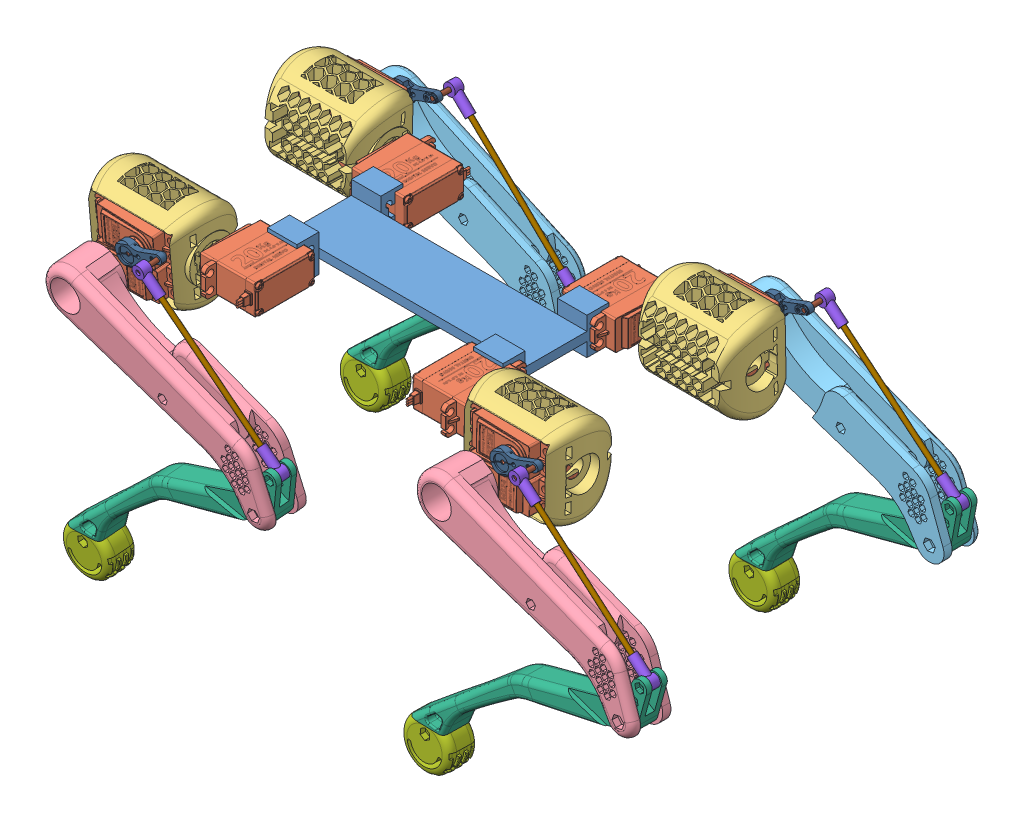
SolidWorks assembly Main_URDF_Assembly, configuration Default. Lengths in mm.
Overall size (432.52 227.74 243.72).
49 component instances, 11 part files, 112 mates.
Components (placement in the parent):
- Main_Body-1: Main_Body [Default] at (5.0922 136.3443 221.2659) size (160 25 72)
- DS3218MG_MS24_Digital_Servo_270-1: DS3218MG_MS24_Digital_Servo_270 [Default] at (145.0922 136.3151 160.5847) x (0 -1 0) z (0 0 1) size (20.1 45.99 55.6)
- DS3218MG_MS24_Digital_Servo_270-2: DS3218MG_MS24_Digital_Servo_270 [Default] at (145.0922 136.3151 281.9471) x (0 1 0) z (0 0 -1) size (20.1 45.99 55.6)
- DS3218MG_MS24_Digital_Servo_270-3: DS3218MG_MS24_Digital_Servo_270 [Default] at (-14.9078 136.3151 160.5847) x (0 1 0) z (0 0 1) size (20.1 45.99 55.6)
- DS3218MG_MS24_Digital_Servo_270-4: DS3218MG_MS24_Digital_Servo_270 [Default] at (-14.9078 136.3151 281.9471) x (0 -1 0) z (0 0 -1) size (20.1 45.99 55.6)
- HipJoint-1: HipJoint [Default] at (191.8422 136.3151 281.9471) x (1 0 0) z (0 0.020151 0.999797) size (67.23 58.77 49.18)
- HipJoint-2: HipJoint [Default] at (191.8422 136.3151 160.5847) x (1 0 0) z (0 0.018154 -0.999835) size (67.23 58.77 49.18)
- HipJoint-3: HipJoint [Default] at (-61.6578 136.3151 160.5847) x (-1 0 0) z (0 -0.032164 -0.999483) size (67.23 58.77 49.18)
- HipJoint-4: HipJoint [Default] at (-61.6578 136.3151 281.9471) x (-1 0 0) z (0 -0.089213 0.996013) size (67.23 58.77 49.18)
- DS3218MG_MS24_Digital_Servo_270-5: DS3218MG_MS24_Digital_Servo_270 [Default] at (-51.4078 146.0222 296.8726) x (0 -0.996013 -0.089213) z (-1 0 0) size (20.1 45.99 55.6)
- DS3218MG_MS24_Digital_Servo_270-6: DS3218MG_MS24_Digital_Servo_270 [Default] at (-71.9078 124.11 294.91) x (0 0.996013 0.089213) z (1 0 0) size (20.1 45.99 55.6)
- DS3218MG_MS24_Digital_Servo_270-7: DS3218MG_MS24_Digital_Servo_270 [Default] at (181.5922 125.5994 296.1659) x (0 0.999797 -0.020151) z (1 0 0) size (20.1 45.99 55.6)
- DS3218MG_MS24_Digital_Servo_270-8: DS3218MG_MS24_Digital_Servo_270 [Default] at (202.0922 147.6949 295.7206) x (0 -0.999797 0.020151) z (-1 0 0) size (20.1 45.99 55.6)
- DS3218MG_MS24_Digital_Servo_270-10: DS3218MG_MS24_Digital_Servo_270 [Default] at (201.5922 147.5674 146.7867) x (0 0.999835 0.018154) z (-1 0 0) size (20.1 45.99 55.6)
- DS3218MG_MS24_Digital_Servo_270-11: DS3218MG_MS24_Digital_Servo_270 [Default] at (182.0922 125.5711 146.3873) x (0 -0.999835 -0.018154) z (1 0 0) size (20.1 45.99 55.6)
- DS3218MG_MS24_Digital_Servo_270-12: DS3218MG_MS24_Digital_Servo_270 [Default] at (-71.4078 124.7705 146.949) x (0 -0.999483 0.032164) z (1 0 0) size (20.1 45.99 55.6)
- DS3218MG_MS24_Digital_Servo_270-13: DS3218MG_MS24_Digital_Servo_270 [Default] at (-51.9078 146.8591 146.2382) x (0 0.999483 -0.032164) z (-1 0 0) size (20.1 45.99 55.6)
- Left_Thigh-1: Left_Thigh [Default] at (238.4344 106.9954 326.3469) x (0 0.020151 0.999797) z (-0.94737 0.320075 -0.006451) size (26.29 49.21 165.28)
- Left_Thigh-2: Left_Thigh [Default] at (-16.0368 99.6656 322.6398) x (0 -0.089213 0.996013) z (-0.931184 0.363097 0.032523) size (26.29 49.21 165.28)
- Right_Thigh-1: Right_Thigh [Default] at (238.6676 105.2996 162.2219) x (0 -0.018154 0.999835) z (-0.942923 0.332955 0.006045) size (26.29 49.21 165.28)
- Right_Thigh-2: Right_Thigh [Default] at (-15.4072 103.7636 163.8334) x (0 0.032164 0.999483) z (-0.933343 0.358799 -0.011546) size (26.29 49.21 165.28)
- Leg_Universal-1: Leg_Universal [Default] at (-18.5337 13.2297 315.3997) x (0 -0.089213 0.996013) z (-0.987227 -0.158687 -0.014214) size (27.56 93.87 164.52)
- Leg_Universal-2: Leg_Universal [Default] at (-18.251 17.1977 120.0951) x (0 0.032164 0.999483) z (-0.989939 -0.14142 0.004551) size (27.56 93.87 164.52)
- Leg_Universal-3: Leg_Universal [Default] at (237.16 22.9219 114.2185) x (0 -0.018154 0.999835) z (-0.990021 -0.1409 -0.002558) size (27.56 93.87 164.52)
- Leg_Universal-4: Leg_Universal [Default] at (235.6218 28.8095 328.4229) x (0 0.020151 0.999797) z (-0.996606 -0.082305 0.001659) size (27.56 93.87 164.52)
- Feet-1: Feet [Default] at (-76.7895 -34.0885 310.9104) x (0 -0.089213 0.996013) z (-0.998583 -0.052998 -0.004747) size (22.41 28.94 33.98)
- Feet-2: Feet [Default] at (173.8572 -14.0583 329.0368) x (0 -0.020151 -0.999797) z (0.999703 -0.024346 0.000491) size (22.41 28.94 33.98)
- Feet-3: Feet [Default] at (178.5295 -23.4953 113.6258) x (0 -0.018154 0.999835) z (-0.999401 -0.034613 -0.000628) size (22.41 28.94 33.98)
- Feet-4: Feet [Default] at (-76.8547 -29.2243 121.8391) x (0 0.032164 0.999483) z (-0.99938 -0.035176 0.001132) size (22.41 28.94 33.98)
- Ball_Bearing_End_Joint-1: Ball_Bearing_End_Joint [Default] at (314.8505 81.1585 327.1177) x (0.639096 0.768971 -0.015498) z (0 -0.020151 -0.999797) size (8 20 6)
- Ball_Bearing_End_Joint-2: Ball_Bearing_End_Joint [Default] at (313.1644 79.8517 115.5023) x (0.650252 0.759593 0.013792) z (0 0.018154 -0.999835) size (8 20 6)
- Ball_Bearing_End_Joint-3: Ball_Bearing_End_Joint [Default] at (56.3978 71.3675 320.3561) x (0.685285 0.725371 0.064972) z (0 0.089213 -0.996013) size (8 20 6)
- Ball_Bearing_End_Joint-4: Ball_Bearing_End_Joint [Default] at (57.7206 74.1637 118.512) x (0.67212 0.74006 -0.023816) z (0 -0.032164 -0.999483) size (8 20 6)
- Long_Metal_Rod-1: Long_Metal_Rod [Default] at (13.4296 111.6381 323.9631) x (-0.174888 -0.098859 -0.979613) z (-0.728275 0.682553 0.061136) size (3 3 100)
- Long_Metal_Rod-2: Long_Metal_Rod [Default] at (14.0344 113.7983 117.2365) x (0.411304 0.478318 0.775913) z (-0.740443 0.671772 -0.021618) size (3 3 100)
- Long_Metal_Rod-3: Long_Metal_Rod [Default] at (269.472 118.8575 326.3579) x (0.046921 0.076552 0.995961) z (0.769127 -0.638967 0.012878) size (3 3 100)
- Long_Metal_Rod-4: Long_Metal_Rod [Default] at (268.341 118.2103 116.1987) x (-0.048668 -0.074954 0.995999) z (-0.759718 0.650145 0.011805) size (3 3 100)
- Servo_arm_25T-1: Servo_arm_25T [Default] at (-51.9078 146.219 126.3485) x (-0.94707 -0.320861 0.010325) z (-0.321027 0.94658 -0.030461) size (33.87 4.68 15)
- Servo_arm_25T-2: Servo_arm_25T [Default] at (201.5922 147.9287 126.89) x (-0.932997 -0.359824 -0.006533) z (-0.359884 0.932843 0.016938) size (33.87 4.68 15)
- Servo_arm_25T-3: Servo_arm_25T [Default] at (202.0922 148.0959 315.6166) x (-0.936228 -0.351321 0.007081) z (0.351392 -0.936038 0.018866) size (33.87 4.68 15)
- Servo_arm_25T-4: Servo_arm_25T [Default] at (-51.4078 144.2469 316.6933) x (-0.930604 -0.364568 -0.032654) z (0.366028 -0.926893 -0.083022) size (33.87 4.68 15)
- Ball_Bearing_End_Joint-5: Ball_Bearing_End_Joint [Default] at (-29.5386 151.9087 327.5702) x (0.685285 0.725371 0.064972) z (0 -0.089213 0.996013) size (8 20 6)
- Ball_Bearing_End_Joint-6: Ball_Bearing_End_Joint [Default] at (224.0935 156.5565 325.5981) x (-0.639096 -0.768971 0.015498) z (0 -0.020151 -0.999797) size (8 20 6)
- Ball_Bearing_End_Joint-7: Ball_Bearing_End_Joint [Default] at (223.5176 156.5688 116.8952) x (0.650252 0.759593 0.013792) z (0 -0.018154 0.999835) size (8 20 6)
- Ball_Bearing_End_Joint-8: Ball_Bearing_End_Joint [Default] at (-29.6517 153.4328 115.9611) x (-0.67212 -0.74006 0.023816) z (0 -0.032164 -0.999483) size (8 20 6)
- Short_Metal_Rod-1: Short_Metal_Rod [Default] at (-29.5386 152.3102 323.0881) x (0.999839 0.017882 0.001602) z (0 -0.089213 0.996013) size (3 3 16.55)
- Short_Metal_Rod-2: Short_Metal_Rod [Default] at (224.0935 156.4658 321.099) x (1 0 0) z (0 0.020151 0.999797) size (3 3 16.55)
- Short_Metal_Rod-3: Short_Metal_Rod [Default] at (223.5176 156.4191 125.1439) x (1 0.000002 0) z (0 -0.018154 0.999835) size (3 3 16.55)
- Short_Metal_Rod-4: Short_Metal_Rod [Default] at (-29.6517 153.6981 124.2068) x (0.999998 -0.001781 0.000057) z (0 0.032164 0.999483) size (3 3 16.55)
Mates (geometry in assembly coordinates):
- Coincident1: coincident anti-aligned: plane of Body-1 through (145.0922 136.3443 251.9471) normal (0 0 1); plane of DS3218MG MS24 Digital Servo 270-2 through (125.0922 126.3151 251.9471) normal (0 0 -1)
- Coincident2: coincident anti-aligned: plane of Body-1 through (145.0922 126.3151 221.2659) normal (0 1 0); plane of DS3218MG MS24 Digital Servo 270-2 through (156.0922 126.3151 290.9471) normal (0 -1 0)
- Coincident3: coincident anti-aligned: plane of Body-1 through (145.0922 136.3443 221.2659) normal (1 0 0); plane of DS3218MG MS24 Digital Servo 270-2 through (145.0922 145.3151 254.9471) normal (-1 0 0)
- Coincident4: coincident anti-aligned: plane of Body-1 through (145.0922 126.3151 221.2659) normal (0 1 0); plane of DS3218MG MS24 Digital Servo 270-1 through (156.0922 126.3151 189.5847) normal (0 -1 0)
- Coincident5: coincident anti-aligned: plane of Body-1 through (145.0922 136.3443 221.2659) normal (1 0 0); plane of DS3218MG MS24 Digital Servo 270-1 through (145.0922 127.3151 187.5847) normal (-1 0 0)
- Coincident6: coincident anti-aligned: plane of Body-1 through (145.0922 136.3443 190.5847) normal (0 0 -1); plane of DS3218MG MS24 Digital Servo 270-1 through (125.0922 146.3151 190.5847) normal (0 0 1)
- Coincident7: coincident anti-aligned: plane of Body-1 through (-14.9078 126.3151 221.2659) normal (0 1 0); plane of DS3218MG MS24 Digital Servo 270-3 through (-25.9078 126.3151 151.5847) normal (0 -1 0)
- Coincident8: coincident anti-aligned: plane of Body-1 through (-14.9078 136.3443 190.5847) normal (0 0 -1); plane of DS3218MG MS24 Digital Servo 270-3 through (5.0922 126.3151 190.5847) normal (0 0 1)
- Coincident9: coincident anti-aligned: plane of Body-1 through (-14.9078 136.3443 221.2659) normal (-1 0 0); plane of DS3218MG MS24 Digital Servo 270-3 through (-14.9078 145.3151 187.5847) normal (1 0 0)
- Coincident15: coincident anti-aligned: plane of Body-1 through (-14.9078 136.3443 251.9471) normal (0 0 1); plane of DS3218MG MS24 Digital Servo 270-4 through (5.0922 146.3151 251.9471) normal (0 0 -1)
- Coincident16: coincident anti-aligned: plane of Body-1 through (-14.9078 126.3151 221.2659) normal (0 1 0); plane of DS3218MG MS24 Digital Servo 270-4 through (5.0922 126.3151 291.9471) normal (0 -1 0)
- Coincident17: coincident anti-aligned: plane of Body-1 through (-14.9078 136.3443 221.2659) normal (-1 0 0); plane of DS3218MG MS24 Digital Servo 270-4 through (-14.9078 127.3151 254.9471) normal (1 0 0)
- Concentric1: concentric aligned: circle of DS3218MG MS24 Digital Servo 270-2; circle of HipJoint-1
- Distance2: distance = 0 mm anti-aligned: plane of DS3218MG MS24 Digital Servo 270-2 through (163.4922 136.3151 281.9471) normal (1 0 0); plane of HipJoint-1 through (163.4922 136.3151 281.9471) normal (-1 0 0)
- Concentric2: concentric aligned: circle of DS3218MG MS24 Digital Servo 270-1; circle of HipJoint-2
- Distance1: distance = 0 mm anti-aligned: plane of HipJoint-2 through (163.4922 136.3151 160.5847) normal (-1 0 0); plane of DS3218MG MS24 Digital Servo 270-1 through (163.4922 136.3151 160.5847) normal (1 0 0)
- Concentric3: concentric aligned: circle of DS3218MG MS24 Digital Servo 270-3; circle of HipJoint-3
- Distance3: distance = 0 mm anti-aligned: plane of HipJoint-3 through (-33.3078 136.3151 160.5847) normal (1 0 0); plane of DS3218MG MS24 Digital Servo 270-3 through (-33.3078 136.3151 160.5847) normal (-1 0 0)
- Concentric4: concentric aligned: circle of DS3218MG MS24 Digital Servo 270-4; circle of HipJoint-4
- Distance4: distance = 0 mm anti-aligned: plane of HipJoint-4 through (-33.3078 136.3151 281.9471) normal (1 0 0); plane of DS3218MG MS24 Digital Servo 270-4 through (-33.3078 136.3151 281.9471) normal (-1 0 0)
- Coincident23: coincident anti-aligned: plane of HipJoint-4 through (-81.9078 137.5641 268.0029) normal (1 0 0); plane of DS3218MG_MS24_Digital_Servo_270-6 through (-81.9078 115.9341 274.0976) normal (-1 0 0)
- Coincident24: coincident anti-aligned: plane of HipJoint-4 through (-61.6578 135.0661 295.8913) normal (0 -0.089213 0.996013); plane of DS3218MG_MS24_Digital_Servo_270-6 through (-44.9078 133.0741 295.7129) normal (0 0.089213 -0.996013)
- Coincident25: coincident anti-aligned: plane of HipJoint-4 through (-61.6578 136.5681 267.9137) normal (0 -0.996013 -0.089213); plane of DS3218MG_MS24_Digital_Servo_270-6 through (-81.9078 135.8543 275.8818) normal (0 0.996013 0.089213)
- Coincident26: coincident anti-aligned: plane of HipJoint-4 through (-41.4078 137.5641 268.0029) normal (-1 0 0); plane of DS3218MG_MS24_Digital_Servo_270-5 through (-41.4078 157.7666 277.8445) normal (1 0 0)
- Coincident27: coincident anti-aligned: plane of HipJoint-4 through (-61.6578 135.0661 295.8913) normal (0 -0.089213 0.996013); plane of DS3218MG_MS24_Digital_Servo_270-5 through (-78.4078 137.0581 296.0697) normal (0 0.089213 -0.996013)
- Coincident28: coincident anti-aligned: plane of HipJoint-4 through (-61.6578 138.5601 268.0922) normal (0 0.996013 0.089213); plane of DS3218MG_MS24_Digital_Servo_270-5 through (-41.4078 137.8464 276.0603) normal (0 -0.996013 -0.089213)
- Coincident29: coincident anti-aligned: plane of HipJoint-1 through (212.0922 136.033 267.95) normal (-1 0 0); plane of DS3218MG MS24 Digital Servo 270-8 through (212.0922 157.2899 275.5232) normal (1 0 0)
- Coincident30: coincident anti-aligned: plane of HipJoint-1; plane of DS3218MG MS24 Digital Servo 270-8
- Coincident31: coincident anti-aligned: plane of HipJoint-1; plane of DS3218MG MS24 Digital Servo 270-8
- Coincident32: coincident anti-aligned: plane of HipJoint-1 through (171.5922 136.033 267.95) normal (1 0 0); plane of DS3218MG MS24 Digital Servo 270-7 through (171.5922 115.1984 276.3715) normal (-1 0 0)
- Coincident33: coincident anti-aligned: plane of HipJoint-1; plane of DS3218MG MS24 Digital Servo 270-7
- Coincident34: coincident anti-aligned: plane of HipJoint-1; plane of DS3218MG MS24 Digital Servo 270-7
- Concentric6: concentric aligned: circle of DS3218MG MS24 Digital Servo 270-6; circle of Left Thigh-2
- Distance18: distance = 2 mm anti-aligned: plane of Left_Thigh-2 through (-71.9078 122.29 315.2286) normal (0 0.089213 -0.996013); plane of DS3218MG_MS24_Digital_Servo_270-6 through (-71.9078 122.4684 313.2366) normal (0 -0.089213 0.996013)
- Concentric7: concentric aligned: circle of DS3218MG MS24 Digital Servo 270-7; circle of Left Thigh-1
- Distance19: distance = 2 mm anti-aligned: plane of Left_Thigh-1 through (181.5922 126.0105 316.5618) normal (0 -0.020151 -0.999797); plane of DS3218MG_MS24_Digital_Servo_270-7 through (181.5922 125.9702 314.5622) normal (0 0.020151 0.999797)
- Coincident37: coincident anti-aligned: plane of HipJoint-2 through (212.0922 136.0609 174.5824) normal (-1 0 0); plane of DS3218MG_MS24_Digital_Servo_270-11 through (212.0922 135.2063 166.5656) normal (1 0 0)
- Coincident38: coincident anti-aligned: plane of HipJoint-2 through (191.8422 135.0611 174.5643) normal (0 -0.999835 -0.018154); plane of DS3218MG_MS24_Digital_Servo_270-11 through (172.0922 135.2063 166.5656) normal (0 0.999835 0.018154)
- Coincident39: coincident anti-aligned: plane of HipJoint-2 through (191.8422 136.5692 146.587) normal (0 0.018154 -0.999835); plane of DS3218MG_MS24_Digital_Servo_270-11 through (209.0922 116.5725 146.224) normal (0 -0.018154 0.999835)
- Coincident40: coincident anti-aligned: plane of HipJoint-2 through (171.5922 136.0609 174.5824) normal (1 0 0); plane of DS3218MG_MS24_Digital_Servo_270-10 through (171.5922 137.206 166.6019) normal (-1 0 0)
- Coincident41: coincident anti-aligned: plane of HipJoint-2 through (191.8422 137.0608 174.6006) normal (0 0.999835 0.018154); plane of DS3218MG_MS24_Digital_Servo_270-10 through (211.5922 137.206 166.6019) normal (0 -0.999835 -0.018154)
- Coincident42: coincident anti-aligned: plane of HipJoint-2 through (191.8422 136.5692 146.587) normal (0 0.018154 -0.999835); plane of DS3218MG_MS24_Digital_Servo_270-10 through (174.5922 156.5659 146.9501) normal (0 -0.018154 0.999835)
- Coincident43: coincident anti-aligned: plane of HipJoint-3 through (-41.4078 136.7654 174.5775) normal (-1 0 0); plane of DS3218MG MS24 Digital Servo 270-11 through (-41.4078 135.4086 166.617) normal (1 0 0)
- Coincident44: coincident anti-aligned: plane of HipJoint-3 through (-61.6578 135.8648 146.592) normal (0 -0.032164 -0.999483); plane of DS3218MG MS24 Digital Servo 270-11 through (-44.4078 115.7752 147.2385) normal (0 0.032164 0.999483)
- Coincident45: coincident anti-aligned: plane of HipJoint-3 through (-61.6578 115.6763 175.2561) normal (0 0.999483 -0.032164); plane of DS3218MG MS24 Digital Servo 270-11 through (-81.4078 115.419 167.2603) normal (0 -0.999483 0.032164)
- Coincident46: coincident anti-aligned: plane of HipJoint-3 through (-81.9078 136.7654 174.5775) normal (1 0 0); plane of DS3218MG MS24 Digital Servo 270-12 through (-81.9078 137.5075 166.5495) normal (-1 0 0)
- Coincident47: coincident anti-aligned: plane of HipJoint-3 through (-61.6578 137.7649 174.5453) normal (0 0.999483 -0.032164); plane of DS3218MG MS24 Digital Servo 270-12 through (-41.9078 137.5075 166.5495) normal (0 -0.999483 0.032164)
- Coincident48: coincident anti-aligned: plane of HipJoint-3 through (-61.6578 135.8648 146.592) normal (0 -0.032164 -0.999483); plane of DS3218MG MS24 Digital Servo 270-12 through (-78.9078 155.8544 145.9487) normal (0 0.032164 0.999483)
- Concentric8: concentric aligned: circle of DS3218MG MS24 Digital Servo 270-9; circle of Right Thigh-1
- Distance20: distance = 2 mm anti-aligned: plane of DS3218MG_MS24_Digital_Servo_270-11 through (182.0922 125.9051 127.9904) normal (0 0.018154 -0.999835); plane of Right_Thigh-1 through (182.0922 125.9414 125.9907) normal (0 -0.018154 0.999835)
- Concentric9: concentric anti-aligned: circle of DS3218MG MS24 Digital Servo 270-11; circle of Right Thigh-2
- Distance21: distance = 2 mm anti-aligned: plane of DS3218MG MS24 Digital Servo 270-11 through (-71.4078 124.1787 128.5585) normal (0 -0.032164 -0.999483); plane of Right Thigh-2 through (-71.4078 124.1144 126.5596) normal (0 0.032164 0.999483)
- Concentric10: concentric anti-aligned: circle of Left Thigh-2; circle of Leg_Universal-1
- Distance10: distance = 0 mm anti-aligned: plane of Leg_Universal-1 through (-18.5337 12.6052 322.3718) normal (0 -0.089213 0.996013); plane of Left_Thigh-2 through (-16.0368 98.9965 330.1099) normal (0 0.089213 -0.996013)
- Concentric11: concentric anti-aligned: circle of Left Thigh-1; circle of Leg_Universal-4
- Distance11: distance = 0 mm anti-aligned: plane of Left_Thigh-1 through (238.4344 107.1466 333.8454) normal (0 -0.020151 -0.999797); plane of Leg_Universal-4 through (235.6218 28.9505 335.4214) normal (0 0.020151 0.999797)
- Concentric12: concentric anti-aligned: circle of Right Thigh-1; circle of Leg_Universal-3
- Distance12: distance = 0 mm anti-aligned: plane of Leg_Universal-3 through (237.16 23.049 107.2197) normal (0 0.018154 -0.999835); plane of Right_Thigh-1 through (238.6676 106.2709 108.7308) normal (0 -0.018154 0.999835)
- Concentric13: concentric anti-aligned: circle of Right Thigh-2; circle of Leg_Universal-2
- Distance13: distance = 0 mm anti-aligned: plane of Leg_Universal-2 through (-18.251 16.9726 113.0987) normal (0 -0.032164 -0.999483); plane of Right Thigh-2 through (-15.4072 102.0429 110.3611) normal (0 0.032164 0.999483)
- Coincident55: coincident anti-aligned: plane of Leg_Universal-1 through (-72.9089 10.7006 311.1571) normal (0.998583 0.052998 0.004747); plane of Feet-1 through (-70.2275 -39.7541 310.4029) normal (-0.998583 -0.052998 -0.004747)
- Coincident56: coincident anti-aligned: plane of Leg_Universal-1 through (-18.5337 12.8728 319.3837) normal (0 -0.089213 0.996013); plane of Feet-1 through (-76.4686 -40.4645 314.6063) normal (0 0.089213 -0.996013)
- Coincident57: coincident anti-aligned: plane of Leg_Universal-1 through (-16.4376 -25.0578 301.9302) normal (0.053211 -0.994602 -0.089087); plane of Feet-1 through (-77.054 -28.0915 299.5944) normal (-0.053211 0.994602 0.089087)
- Coincident58: coincident anti-aligned: plane of Leg_Universal-4 through (235.6218 28.8901 332.4221) normal (0 0.020151 0.999797); plane of Feet-2 through (173.7104 -19.9991 333.4074) normal (0 -0.020151 -0.999797)
- Coincident59: coincident anti-aligned: plane of Leg_Universal-4 through (181.1856 30.0546 324.397) normal (0.999703 -0.024346 0.000491); plane of Feet-2 through (179.9585 -20.2369 329.1613) normal (-0.999703 0.024346 -0.000491)
- Coincident60: coincident anti-aligned: plane of Leg_Universal-4 through (234.6625 -10.7646 319.2184) normal (-0.024351 -0.9995 0.020145); plane of Feet-2 through (173.9782 -8.8524 340.7401) normal (0.024351 0.9995 -0.020145)
- Coincident61: coincident anti-aligned: plane of Leg_Universal-3 through (237.16 22.9945 110.2192) normal (0 0.018154 -0.999835); plane of Feet-3 through (178.7383 -29.443 109.2671) normal (0 -0.018154 0.999835)
- Coincident62: coincident anti-aligned: plane of Leg_Universal-3 through (170.7475 20.6944 110.1774) normal (-0.999401 -0.034613 -0.000628); plane of Feet-3 through (172.492 -29.7364 113.5125) normal (0.999401 0.034613 0.000628)
- Coincident63: coincident anti-aligned: plane of Leg_Universal-3 through (238.5237 -16.2587 103.5055) normal (0.034619 -0.999236 -0.018143); plane of Feet-3 through (178.3575 -18.3142 101.9121) normal (-0.034619 0.999236 0.018143)
- Coincident64: coincident anti-aligned: plane of Feet-4 through (-82.8886 -35.4667 122.04) normal (0.99938 0.035176 -0.001132); plane of Leg_Universal-2 through (-84.6622 14.7315 116.1724) normal (-0.99938 -0.035176 0.001132)
- Coincident66: coincident anti-aligned: plane of Leg_Universal-2 through (-16.8646 -22.4714 111.3665) normal (0.035194 -0.998863 0.032144); plane of Feet-4 through (-77.0297 -24.6391 109.8796) normal (-0.035194 0.998863 -0.032144)
- Coincident67: coincident anti-aligned: plane of Leg_Universal-2 through (-18.251 17.0691 116.0971) normal (0 -0.032164 -0.999483); plane of Feet-4 through (-76.6425 -35.3836 117.7851) normal (0 0.032164 0.999483)
- Coincident68: coincident aligned: circle of Leg_Universal-4; circle of ball bearing end joint-1
- Coincident69: coincident anti-aligned: circle of Leg_Universal-3; circle of ball bearing end joint-2
- Coincident70: coincident anti-aligned: circle of Leg_Universal-2; circle of ball bearing end joint-4
- Coincident71: coincident aligned: circle of Leg_Universal-1; circle of ball bearing end joint-3
- Concentric14: concentric aligned: cylinder of Ball_Bearing_End_Joint-2 through (306.3269 85.703 115.6085) axis (-0.759718 0.650145 0.011805) radius 1.5; cylinder of Long_Metal_Rod-4 through (306.3269 85.703 115.6085) axis (-0.759718 0.650145 0.011805) radius 1.5
- Concentric15: concentric anti-aligned: cylinder of ball bearing end joint-1 through (307.9284 86.9092 327.0018) axis (-0.769127 0.638967 -0.012878) radius 1.5; cylinder of long-3 through (231.0157 150.8058 325.714) axis (0.769127 -0.638967 0.012878) radius 1.5
- Concentric16: concentric aligned: cylinder of Ball_Bearing_End_Joint-3 through (49.8433 77.5105 320.9063) axis (-0.728275 0.682553 0.061136) radius 1.5; cylinder of Long_Metal_Rod-1 through (49.8433 77.5105 320.9063) axis (-0.728275 0.682553 0.061136) radius 1.5
- Concentric17: concentric aligned: cylinder of ball bearing end joint-4 through (51.0566 80.2097 118.3174) axis (-0.740443 0.671772 -0.021618) radius 1.5; cylinder of long-2 through (51.0566 80.2097 118.3174) axis (-0.740443 0.671772 -0.021618) radius 1.5
- Concentric25: concentric anti-aligned: cylinder of Long_Metal_Rod-1 through (49.8433 77.5105 320.9063) axis (-0.728275 0.682553 0.061136) radius 1.5; cylinder of Ball_Bearing_End_Joint-5 through (-22.9842 145.7658 327.02) axis (0.728275 -0.682553 -0.061136) radius 1.5
- Concentric23: concentric anti-aligned: cylinder of Long_Metal_Rod-4 through (306.3269 85.703 115.6085) axis (-0.759718 0.650145 0.011805) radius 1.5; cylinder of Ball_Bearing_End_Joint-7 through (230.3551 150.7175 116.789) axis (0.759718 -0.650145 -0.011805) radius 1.5
- Concentric22: concentric anti-aligned: cylinder of long-2 through (51.0566 80.2097 118.3174) axis (-0.740443 0.671772 -0.021618) radius 1.5; cylinder of ball bearing end joint-8 through (-22.9877 147.3868 116.1556) axis (0.740443 -0.671772 0.021618) radius 1.5
- Concentric24: concentric aligned: cylinder of long-3 through (231.0157 150.8058 325.714) axis (0.769127 -0.638967 0.012878) radius 1.5; cylinder of ball bearing end joint-6 through (231.0157 150.8058 325.714) axis (0.769127 -0.638967 0.012878) radius 1.5
- Distance14: distance = 0 mm anti-aligned: plane of ball bearing end joint-4 through (51.0566 80.2097 118.3174) normal (-0.740443 0.671772 -0.021618); plane of long-2 through (51.0566 80.2097 118.3174) normal (0.740443 -0.671772 0.021618)
- Distance15: distance = 0 mm anti-aligned: plane of Ball_Bearing_End_Joint-2 through (306.3269 85.703 115.6085) normal (-0.759718 0.650145 0.011805); plane of Long_Metal_Rod-4 through (306.3269 85.703 115.6085) normal (0.759718 -0.650145 -0.011805)
- Distance16: distance = 0 mm anti-aligned: plane of Ball_Bearing_End_Joint-1 through (307.9284 86.9092 327.0018) normal (-0.769127 0.638967 -0.012878); plane of Long_Metal_Rod-3 through (307.9284 86.9092 327.0018) normal (0.769127 -0.638967 0.012878)
- Distance17: distance = 0 mm anti-aligned: plane of Ball_Bearing_End_Joint-3 through (49.8433 77.5105 320.9063) normal (-0.728275 0.682553 0.061136); plane of Long_Metal_Rod-1 through (49.8433 77.5105 320.9063) normal (0.728275 -0.682553 -0.061136)
- Concentric18: concentric anti-aligned: circle of DS3218MG MS24 Digital Servo 270-10; circle of Servo_arm_25T-2
- Distance22: distance = 0 mm anti-aligned: plane of DS3218MG_MS24_Digital_Servo_270-10 through (201.5922 147.9015 128.3898) normal (0 0.018154 -0.999835); plane of Servo_arm_25T-2 through (201.5922 147.9015 128.3898) normal (0 -0.018154 0.999835)
- Concentric19: concentric anti-aligned: circle of DS3218MG MS24 Digital Servo 270-12; circle of Servo_arm_25T-1
- Distance23: distance = 0 mm anti-aligned: plane of DS3218MG MS24 Digital Servo 270-12 through (-51.9078 146.2673 127.8477) normal (0 -0.032164 -0.999483); plane of Servo_arm_25T-1 through (-51.9078 146.2673 127.8477) normal (0 0.032164 0.999483)
- Concentric20: concentric anti-aligned: circle of DS3218MG MS24 Digital Servo 270-5; circle of Servo_arm_25T-4
- Distance24: distance = 0 mm anti-aligned: plane of DS3218MG_MS24_Digital_Servo_270-5 through (-51.4078 144.3807 315.1993) normal (0 -0.089213 0.996013); plane of Servo_arm_25T-4 through (-51.4078 144.3807 315.1993) normal (0 0.089213 -0.996013)
- Concentric21: concentric aligned: circle of DS3218MG MS24 Digital Servo 270-8; circle of Servo_arm_25T-3
- Distance25: distance = 0 mm anti-aligned: plane of DS3218MG_MS24_Digital_Servo_270-8 through (202.0922 148.0657 314.1169) normal (0 0.020151 0.999797); plane of Servo_arm_25T-3 through (202.0922 148.0657 314.1169) normal (0 -0.020151 -0.999797)
- Distance26: distance = 0 mm anti-aligned: plane of long-2 through (-22.9877 147.3868 116.1556) normal (-0.740443 0.671772 -0.021618); plane of ball bearing end joint-8 through (-22.9877 147.3868 116.1556) normal (0.740443 -0.671772 0.021618)
- Distance28: distance = 0 mm anti-aligned: plane of Ball_Bearing_End_Joint-7 through (230.3551 150.7175 116.789) normal (0.759718 -0.650145 -0.011805); plane of Long_Metal_Rod-4 through (230.3551 150.7175 116.789) normal (-0.759718 0.650145 0.011805)
- Distance29: distance = 0 mm anti-aligned: plane of Ball_Bearing_End_Joint-6 through (231.0157 150.8058 325.714) normal (0.769127 -0.638967 0.012878); plane of Long_Metal_Rod-3 through (231.0157 150.8058 325.714) normal (-0.769127 0.638967 -0.012878)
- Distance30: distance = 0 mm anti-aligned: plane of Ball_Bearing_End_Joint-5 through (-22.9842 145.7658 327.02) normal (0.728275 -0.682553 -0.061136); plane of Long_Metal_Rod-1 through (-22.9842 145.7658 327.02) normal (-0.728275 0.682553 0.061136)
- Concentric28: concentric aligned: circle of Servo_arm_25T-3; circle of short-2
- Concentric29: concentric anti-aligned: circle of Servo_arm_25T-2; circle of short-3
- Distance31: distance = 0 mm aligned: plane of Short_Metal_Rod-3 through (223.5176 156.3029 131.5428) normal (0 -0.018154 0.999835); plane of Servo_arm_25T-2 through (220.7851 158.0621 131.5748) normal (0 -0.018154 0.999835)
- Concentric30: concentric anti-aligned: circle of Servo_arm_25T-1; circle of short-4
- Distance32: distance = 0 mm aligned: plane of short-4 through (-29.6517 153.904 130.6035) normal (0 0.032164 0.999483); plane of Servo_arm_25T-1 through (-32.3092 155.7739 130.5433) normal (0 0.032164 0.999483)
- Concentric31: concentric aligned: circle of Servo_arm_25T-4; circle of short-1
- Distance34: distance = 0 mm aligned: plane of Servo_arm_25T-4 through (-30.361 150.084 312.6981) normal (0 0.089213 -0.996013); plane of Short_Metal_Rod-1 through (-29.5386 153.2157 312.9786) normal (0 0.089213 -0.996013)
- Concentric32: concentric anti-aligned: cylinder of ball bearing end joint-8 through (-29.6517 153.5293 118.9595) axis (0 -0.032164 -0.999483) radius 1.5; cylinder of short-4 through (-29.6517 153.3717 114.0621) axis (0 0.032164 0.999483) radius 1.5
- Concentric33: concentric aligned: cylinder of Ball_Bearing_End_Joint-7 through (223.5176 156.6233 113.8957) axis (0 -0.018154 0.999835) radius 1.5; cylinder of Short_Metal_Rod-3 through (223.5176 156.6033 114.9955) axis (0 -0.018154 0.999835) radius 1.5
- Concentric34: concentric anti-aligned: cylinder of ball bearing end joint-6 through (224.0935 156.617 328.5975) axis (0 -0.020151 -0.999797) radius 1.5; cylinder of short-2 through (224.0935 156.2613 310.9511) axis (0 0.020151 0.999797) radius 1.5
- Distance35: distance = 0 mm aligned: plane of Short_Metal_Rod-2 through (224.0935 156.2613 310.9511) normal (0 -0.020151 -0.999797); plane of Servo_arm_25T-3 through (223.2219 153.131 311.0142) normal (0 -0.020151 -0.999797)
- Concentric35: concentric aligned: cylinder of Ball_Bearing_End_Joint-5 through (-29.5386 152.1764 324.5822) axis (0 -0.089213 0.996013) radius 1.5; cylinder of Short_Metal_Rod-1 through (-29.5386 153.2157 312.9786) axis (0 -0.089213 0.996013) radius 1.5
